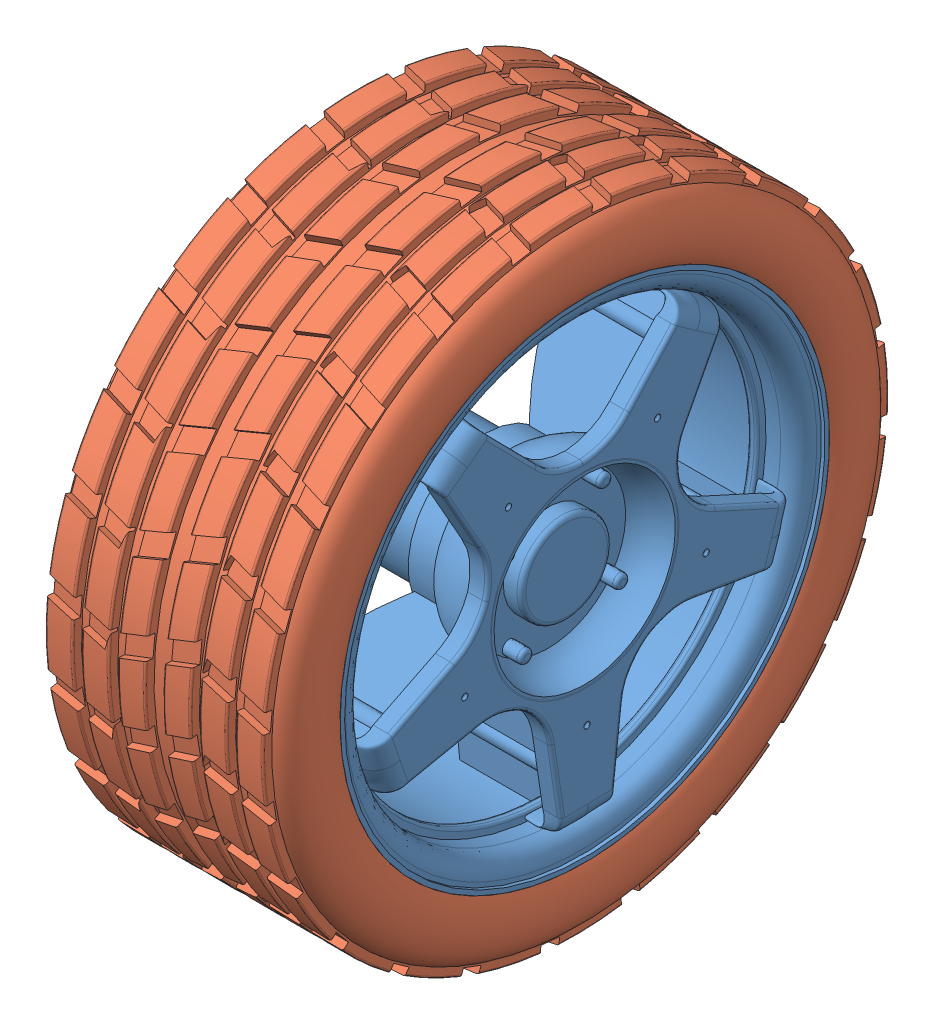
SolidWorks assembly Wheel Assembly, configuration Default. Lengths in mm.
Overall size (31.04 75.43 75.43).
2 component instances, 2 part files, 4 mates.
Components (placement in the parent):
- Wheel-1: Wheel [Default] at (15.129 35.8545 27.9763) x (1 0 0) z (0 0.573638 0.819109) size (30.09 54 54)
- Tyre-2: Tyre [Default] at (15.129 35.8545 27.9763) x (1 0 0) z (0 0.096245 0.995358) size (28.08 69.1 69.1)
Mates (geometry in assembly coordinates):
- Concentric1: concentric: cylinder of ? through (-10.1599 35.8545 27.9763) axis (-1 0 0) radius 27; cylinder of Wheel-1 through (-10.1599 35.8545 27.9763) axis (-1 0 0) radius 27
- Coincident1: coincident: circle of ?; circle of Wheel-1
- Concentric3: concentric: cylinder of assembly; cylinder of assembly; cylinder of Wheel-1 through (-10.1599 35.8545 27.9763) axis (-1 0 0) radius 27; cylinder of Tyre-2 through (-10.1599 35.8545 27.9763) axis (-1 0 0) radius 27
- Coincident3: coincident: plane of assembly; plane of assembly; plane of Wheel-1 through (4.129 56.5779 13.4632) normal (1 0 0); plane of Tyre-2 through (4.129 61.037 25.5412) normal (-1 0 0)
